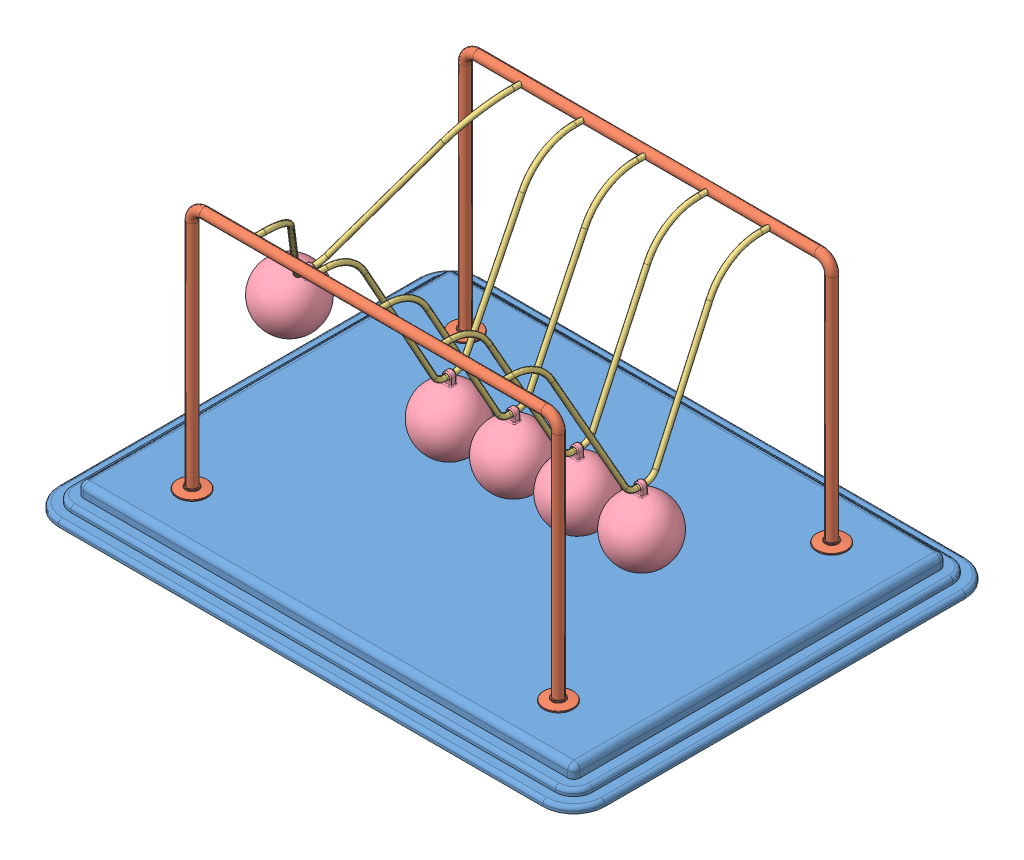
SolidWorks assembly Newtons Cradle NewtonsCradle 0239, configuration Default. Lengths in mm.
Overall size (440 222 340).
13 component instances, 4 part files, 34 mates.
Components (placement in the parent):
- Base NewtonsCradle 0239-1: Base NewtonsCradle 0239 [Default] at (-16.2968 -4.1587 11.425) size (440 20 340)
- frame NewtonsCradle 0239-1: frame NewtonsCradle 0239 [Default] at (-16.2968 144.4547 -98.575) size (319 202 24)
- frame NewtonsCradle 0239-2: frame NewtonsCradle 0239 [Default] at (-16.2968 144.4547 121.425) x (-1 0 0) z (0 0 -1) size (319 202 24)
- Hanging thing NewtonsCradle 0239-1: Hanging thing NewtonsCradle 0239 [Default] at (-157.6326 134.1825 11.425) x (0 0 1) z (-0.859985 0.510319 0) size (220 129 4)
- Hanging thing NewtonsCradle 0239-2: Hanging thing NewtonsCradle 0239 [Default] at (-66.576 122.8418 11.425) x (0 0 1) z (-0.999994 0.003446 0) size (220 129 4)
- Hanging thing NewtonsCradle 0239-3: Hanging thing NewtonsCradle 0239 [Default] at (-15.6923 122.8436 11.425) x (0 0 1) z (-0.999972 -0.007464 0) size (220 129 4)
- Hanging thing NewtonsCradle 0239-4: Hanging thing NewtonsCradle 0239 [Default] at (35.2213 122.8555 11.425) x (0 0 1) z (-0.999824 -0.018742 0) size (220 129 4)
- Hanging thing NewtonsCradle 0239-5: Hanging thing NewtonsCradle 0239 [Default] at (86.0287 122.8747 11.425) x (0 0 1) z (-0.999588 -0.028711 0) size (220 129 4)
- Sphere NewtonsCradle 0239-1: Sphere NewtonsCradle 0239 [Default] at (-195.3962 70.5436 11.425) x (0.859985 -0.510319 0) z (0 0 1) size (50 58.5 50)
- Sphere NewtonsCradle 0239-2: Sphere NewtonsCradle 0239 [Default] at (88.1533 48.9052 11.425) x (0.999588 0.028711 0) z (0 0 1) size (50 58.5 50)
- Sphere NewtonsCradle 0239-3: Sphere NewtonsCradle 0239 [Default] at (-15.14 48.8456 11.425) x (0.999972 0.007464 0) z (0 0 1) size (50 58.5 50)
- Sphere NewtonsCradle 0239-4: Sphere NewtonsCradle 0239 [Default] at (36.6081 48.8685 11.425) x (0.999824 0.018742 0) z (0 0 1) size (50 58.5 50)
- Sphere NewtonsCradle 0239-5: Sphere NewtonsCradle 0239 [Default] at (-66.831 48.8422 11.425) x (0.999994 -0.003446 0) z (0 0 1) size (50 58.5 50)
Mates (geometry in assembly coordinates):
- Coincident1: coincident anti-aligned: plane of Base-1 through (-211.2968 5.8413 156.425) normal (0 1 0); plane of frame-2 through (-175.7968 5.8413 121.425) normal (0 -1 0)
- Coincident2: coincident anti-aligned: plane of Base-1 through (-211.2968 5.8413 156.425) normal (0 1 0); plane of frame-1 through (143.2032 5.8413 -98.575) normal (0 -1 0)
- Concentric1: concentric anti-aligned: cylinder of frame-1 through (-116.2968 203.8413 -94.575) axis (0 0 -1) radius 2; cylinder of frame-2 through (-116.2968 203.8413 117.425) axis (0 0 1) radius 2
- Concentric2: concentric anti-aligned: cylinder of frame-1 through (83.7032 203.8413 -94.575) axis (0 0 -1) radius 2; cylinder of frame-2 through (83.7032 203.8413 117.425) axis (0 0 1) radius 2
- Distance1: distance = 60 mm: plane of frame-1 through (-16.2968 144.4547 -98.575) normal (0 0 1); line of Base-1 through (-211.2968 -12.1587 -158.575) axis (1 0 0)
- Distance2: distance = 60 mm: line of Base-1 through (178.7032 -12.1587 181.425) axis (-1 0 0); plane of frame-2 through (-16.2968 144.4547 121.425) normal (0 0 -1)
- Distance3: distance = 220 mm: plane of frame-2 through (-16.2968 144.4547 121.425) normal (-1 0 0); line of Base-1 through (-236.2968 -12.1587 156.425) axis (0 0 -1)
- Concentric3: concentric anti-aligned: cylinder of frame-1 through (-116.2968 203.8413 -94.575) axis (0 0 -1) radius 2; cylinder of Hanging thing-1 through (-116.2968 203.8413 111.425) axis (0 0 1) radius 2
- Concentric4: concentric anti-aligned: cylinder of frame-1 through (-116.2968 203.8413 -94.575) axis (0 0 -1) radius 2; cylinder of Hanging thing-1 through (-116.2968 203.8413 -98.575) axis (0 0 1) radius 2
- Concentric5: concentric aligned: cylinder of frame-2 through (-66.2968 203.8413 117.425) axis (0 0 1) radius 2; cylinder of Hanging thing-2 through (-66.2968 203.8413 111.425) axis (0 0 1) radius 2
- Concentric6: concentric aligned: cylinder of frame-2 through (-16.2968 203.8413 117.425) axis (0 0 1) radius 2; cylinder of Hanging thing-3 through (-16.2968 203.8413 111.425) axis (0 0 1) radius 2
- Concentric7: concentric aligned: cylinder of frame-2 through (33.7032 203.8413 117.425) axis (0 0 1) radius 2; cylinder of Hanging thing-4 through (33.7032 203.8413 111.425) axis (0 0 1) radius 2
- Concentric8: concentric aligned: cylinder of frame-2 through (83.7032 203.8413 117.425) axis (0 0 1) radius 2; cylinder of Hanging thing-5 through (83.7032 203.8413 111.425) axis (0 0 1) radius 2
- Coincident5: coincident anti-aligned: plane of frame-2 through (83.7032 203.8413 121.425) normal (0 0 -1); plane of Hanging thing-5 through (83.7032 203.8413 121.425) normal (0 0 1)
- Coincident6: coincident anti-aligned: plane of frame-2 through (33.7032 203.8413 121.425) normal (0 0 -1); plane of Hanging thing-4 through (33.7032 203.8413 121.425) normal (0 0 1)
- Coincident7: coincident anti-aligned: plane of frame-2 through (-16.2968 203.8413 121.425) normal (0 0 -1); plane of Hanging thing-3 through (-16.2968 203.8413 121.425) normal (0 0 1)
- Coincident8: coincident anti-aligned: plane of frame-2 through (-66.2968 203.8413 121.425) normal (0 0 -1); plane of Hanging thing-2 through (-66.2968 203.8413 121.425) normal (0 0 1)
- Coincident9: coincident anti-aligned: plane of frame-2 through (-116.2968 203.8413 121.425) normal (0 0 -1); plane of Hanging thing-1 through (-116.2968 203.8413 121.425) normal (0 0 1)
- Concentric9: concentric anti-aligned: cylinder of Hanging thing-1 through (-117.0163 78.8434 7.925) axis (0 0 1) radius 2; cylinder of Sphere-1 through (-117.0163 78.8434 13.925) axis (0 0 -1) radius 2
- Concentric13: concentric anti-aligned: cylinder of Hanging thing-2 through (-66.7276 78.842 7.925) axis (0 0 1) radius 2; cylinder of Sphere-5 through (-66.7276 78.842 13.925) axis (0 0 -1) radius 2
- Concentric15: concentric anti-aligned: cylinder of Hanging thing-3 through (-15.3639 78.8448 7.925) axis (0 0 1) radius 2; cylinder of Sphere-3 through (-15.3639 78.8448 13.925) axis (0 0 -1) radius 2
- Concentric16: concentric anti-aligned: cylinder of Hanging thing-5 through (87.292 78.8928 7.925) axis (0 0 1) radius 2; cylinder of Sphere-2 through (87.292 78.8928 13.925) axis (0 0 -1) radius 2
- Concentric17: concentric anti-aligned: cylinder of Hanging thing-4 through (36.0459 78.8632 7.925) axis (0 0 1) radius 2; cylinder of Sphere-4 through (36.0459 78.8632 13.925) axis (0 0 -1) radius 2
- Parallel1: parallel anti-aligned: plane of Hanging thing-1; plane of Sphere-1
- Coincident22: coincident anti-aligned: plane of Hanging thing-1; plane of Sphere-1
- Coincident12: coincident aligned: plane of Hanging thing-2 through (-66.576 122.8418 11.425) normal (0 0 1); plane of Sphere-5 through (-66.831 48.8422 11.425) normal (0 0 1)
- Coincident10: coincident aligned: plane of Hanging thing-1 through (-116.763 122.8426 11.425) normal (0 0 1); plane of Sphere-1 through (-118.5806 48.8842 11.425) normal (0 0 1)
- Coincident13: coincident anti-aligned: plane of Hanging thing-2 through (-66.576 122.8418 11.425) normal (-0.999994 0.003446 0); plane of Sphere-5 through (-66.831 48.8422 11.425) normal (0.999994 -0.003446 0)
- Coincident14: coincident anti-aligned: plane of Hanging thing-3 through (-15.6923 122.8436 11.425) normal (-0.999972 -0.007464 0); plane of Sphere-3 through (-15.14 48.8456 11.425) normal (0.999972 0.007464 0)
- Coincident15: coincident aligned: plane of Hanging thing-3 through (-15.6923 122.8436 11.425) normal (0 0 1); plane of Sphere-3 through (-15.14 48.8456 11.425) normal (0 0 1)
- Coincident18: coincident aligned: plane of Hanging thing-4 through (35.2213 122.8555 11.425) normal (0 0 1); plane of Sphere-4 through (36.6081 48.8685 11.425) normal (0 0 1)
- Coincident19: coincident anti-aligned: plane of Hanging thing-4 through (35.2213 122.8555 11.425) normal (-0.999824 -0.018742 0); plane of Sphere-4 through (36.6081 48.8685 11.425) normal (0.999824 0.018742 0)
- Coincident20: coincident anti-aligned: plane of Hanging thing-5 through (86.0287 122.8747 11.425) normal (-0.999588 -0.028711 0); plane of Sphere-2 through (88.1533 48.9052 11.425) normal (0.999588 0.028711 0)
- Coincident21: coincident aligned: plane of Hanging thing-5 through (86.0287 122.8747 11.425) normal (0 0 1); plane of Sphere-2 through (88.1533 48.9052 11.425) normal (0 0 1)
